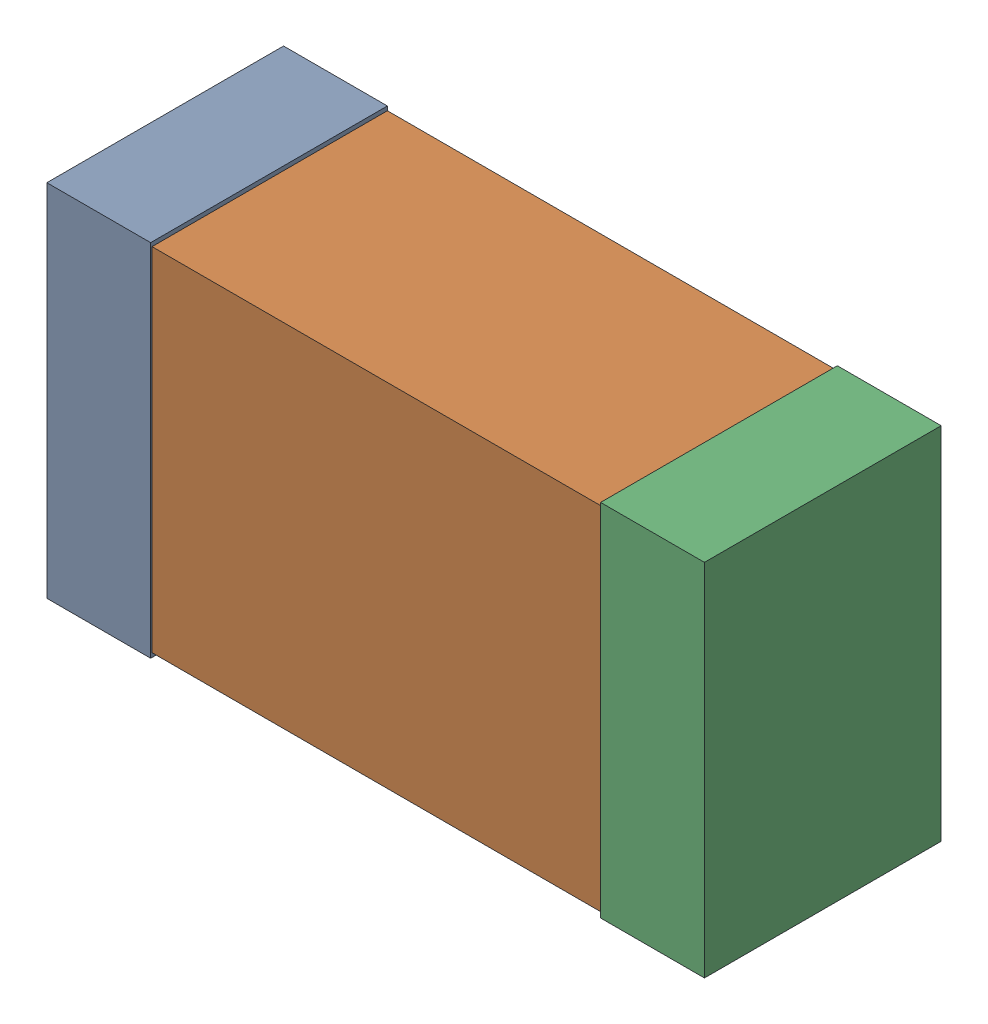
SolidWorks assembly USB45_C9, configuration Default. Lengths in mm.
Overall size (2.38 1.3 0.85).
6 component instances, 2 part files, 0 mates.
Components (placement in the parent):
- 384311232-1: 384311232 [Default] at (148.86 41.275 0) size (0.38 1.3 0.85)
  - Extruded_8-1: Extruded_8 [Default] at origin size (0.38 1.3 0.85)
- 384311360-1: 384311360 [Default] at (149.86 41.275 0) size (2.2 1.27 0.85)
  - Extruded_9-1: Extruded_9 [Default] at origin size (2.2 1.27 0.85)
- 384311232-2: 384311232 [Default] at (150.86 41.275 0) size (0.38 1.3 0.85)
  - Extruded_8-1: Extruded_8 [Default] at origin size (0.38 1.3 0.85)
